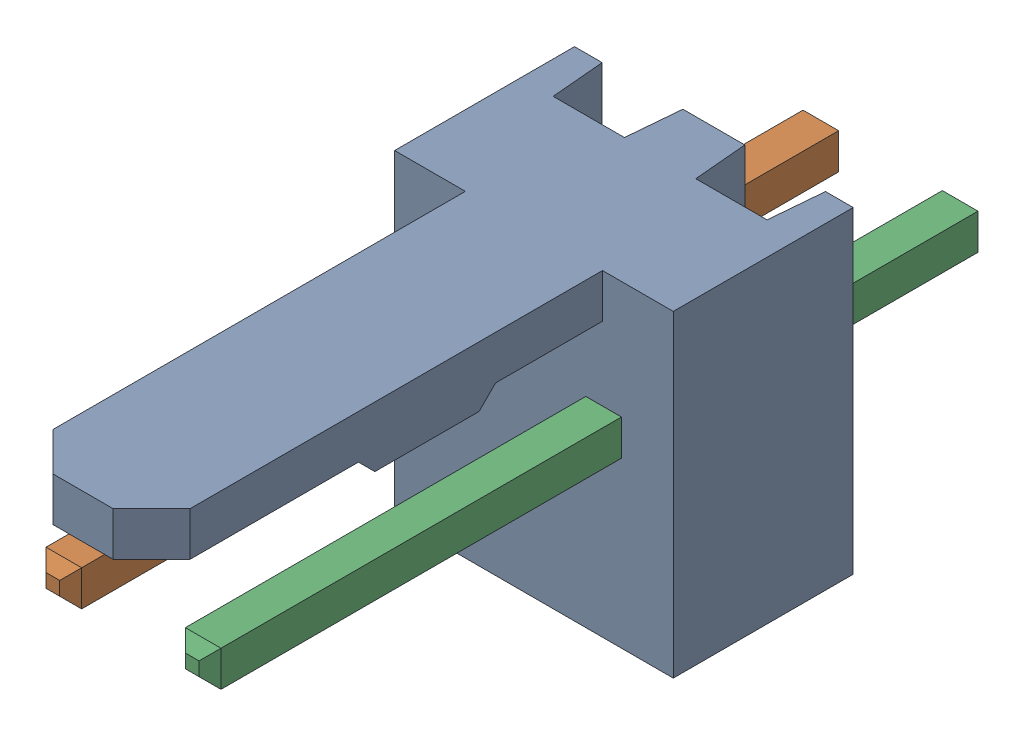
SolidWorks assembly Molex PCB 2 pin v2 (6), configuration Default. Lengths in mm.
Overall size (5.08 5.79 14.92).
3 component instances, 2 part files, 0 mates.
Components (placement in the parent):
- BASE9710016-1: BASE9710016 [Default] at (2.54 2.895 -8.22) size (5.08 5.79 11.5)
- PINO9710016-1: PINO9710016 [Default] at (1.27 3.325 -0.72) size (0.65 0.65 14.2)
- PINO9710016-2: PINO9710016 [Default] at (3.81 3.325 -0.72) size (0.65 0.65 14.2)
